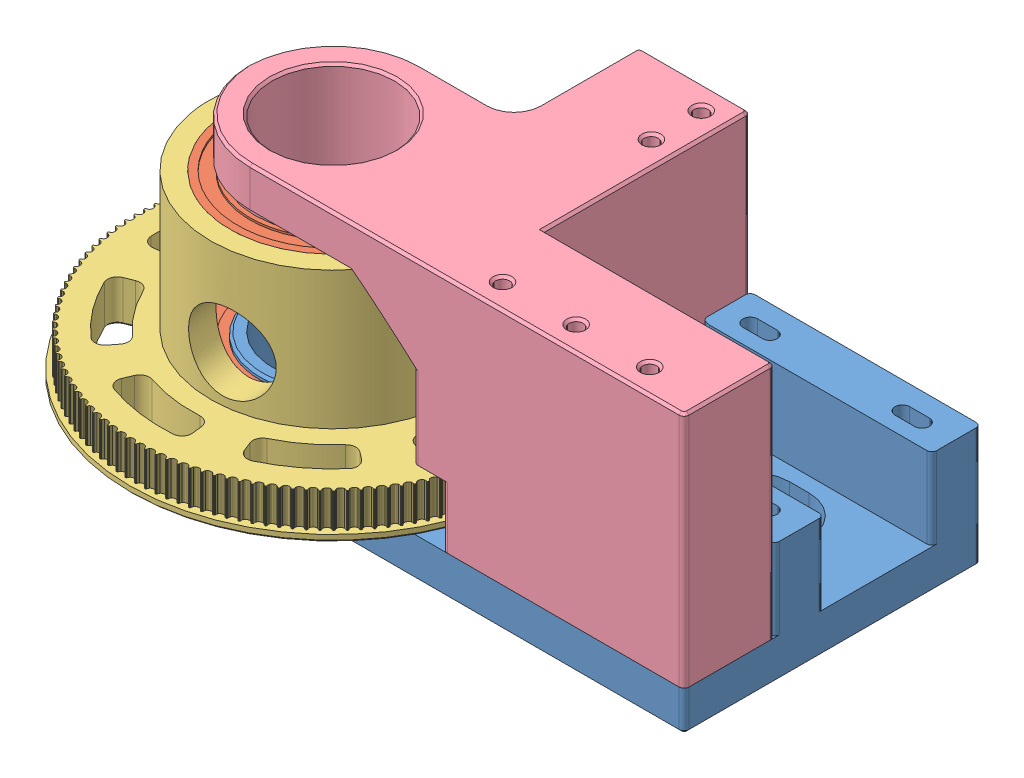
SolidWorks assembly single_belt_8to1, configuration Default. Lengths in mm.
Overall size (135.3 56.5 92.6).
6 component instances, 5 part files, 11 mates.
Components (placement in the parent):
- motor_mount_2020-07-11-a-1: motor_mount_2020-07-11-a [Default] at (2.6939 38.9745 97.2137) size (106.49 24.5 60.5)
- bearing_30x42x7mm-1: bearing_30x42x7mm [Default] at (2.6939 48.9745 97.2137) size (42 7 42)
- gt2_128T_2mm_2020-07-11-a-1: gt2_128T_2mm_2020-07-11-a [Default] at (2.6939 50.4745 97.2137) x (-0.99229 0 0.123941) z (0 1 0) size (82.95 82.95 36.5)
- bearing_30x42x7mm-2: bearing_30x42x7mm [Default] at (2.6939 78.4745 97.2137) x (0.984766 0 0.173884) z (-0.173884 0 0.984766) size (42 7 42)
- bearing_mount_2020-07-11-a-1: bearing_mount_2020-07-11-a [Default] at (2.6939 87.4745 97.2137) size (106.49 48.5 60.5)
- GT2_idle_pulley-1: GT2_idle_pulley [Default] at (49.6939 49.4745 77.2137) size (13 8.7 13)
Mates (geometry in assembly coordinates):
- Concentric1: concentric aligned: cylinder of motor_mount_2020-07-11-a-1 through (2.6939 56.9745 97.2137) axis (0 -1 0) radius 15; cylinder of bearing_30x42x7mm-1 through (2.6939 55.9745 97.2137) axis (0 -1 0) radius 15
- Coincident1: coincident anti-aligned: plane of motor_mount_2020-07-11-a-1 through (2.6939 48.9745 97.2137) normal (0 1 0); plane of bearing_30x42x7mm-1 through (2.6939 48.9745 97.2137) normal (0 -1 0)
- Concentric2: concentric aligned: cylinder of bearing_30x42x7mm-1 through (2.6939 55.9745 97.2137) axis (0 -1 0) radius 21; cylinder of gt2_128T_2mm_2020-07-11-a-1 through (2.6939 55.9745 97.2137) axis (0 -1 0) radius 21
- Coincident2: coincident anti-aligned: plane of bearing_30x42x7mm-1 through (2.6939 55.9745 97.2137) normal (0 1 0); plane of gt2_128T_2mm_2020-07-11-a-1 through (2.6939 55.9745 97.2137) normal (0 -1 0)
- Concentric3: concentric anti-aligned: cylinder of gt2_128T_2mm_2020-07-11-a-1 through (2.6939 78.4745 97.2137) axis (0 1 0) radius 21; cylinder of bearing_30x42x7mm-2 through (2.6939 85.4745 97.2137) axis (0 -1 0) radius 21
- Coincident3: coincident anti-aligned: plane of gt2_128T_2mm_2020-07-11-a-1 through (2.6939 78.4745 97.2137) normal (0 1 0); plane of bearing_30x42x7mm-2 through (2.6939 78.4745 97.2137) normal (0 -1 0)
- Concentric4: concentric anti-aligned: cylinder of bearing_30x42x7mm-2 through (2.6939 85.4745 97.2137) axis (0 -1 0) radius 15; cylinder of bearing_mount_2020-07-11-a-1 through (2.6939 77.4745 97.2137) axis (0 1 0) radius 15
- Coincident4: coincident anti-aligned: plane of bearing_30x42x7mm-2 through (2.6939 85.4745 97.2137) normal (0 1 0); plane of bearing_mount_2020-07-11-a-1 through (2.6939 85.4745 97.2137) normal (0 -1 0)
- Coincident5: coincident aligned: plane of motor_mount_2020-07-11-a-1 through (-14.8061 46.9745 114.7137) normal (0 0 1); plane of bearing_mount_2020-07-11-a-1 through (-14.8061 95.4745 114.7137) normal (0 0 1)
- Concentric5: concentric aligned: cylinder of motor_mount_2020-07-11-a-1 through (49.6939 46.9745 77.2137) axis (0 -1 0) radius 1.425; cylinder of GT2_idle_pulley-1 through (49.6939 58.1745 77.2137) axis (0 -1 0) radius 1.5
- Coincident6: coincident anti-aligned: plane of motor_mount_2020-07-11-a-1 through (49.6939 49.4745 77.2137) normal (0 1 0); plane of GT2_idle_pulley-1 through (49.6939 49.4745 77.2137) normal (0 -1 0)
